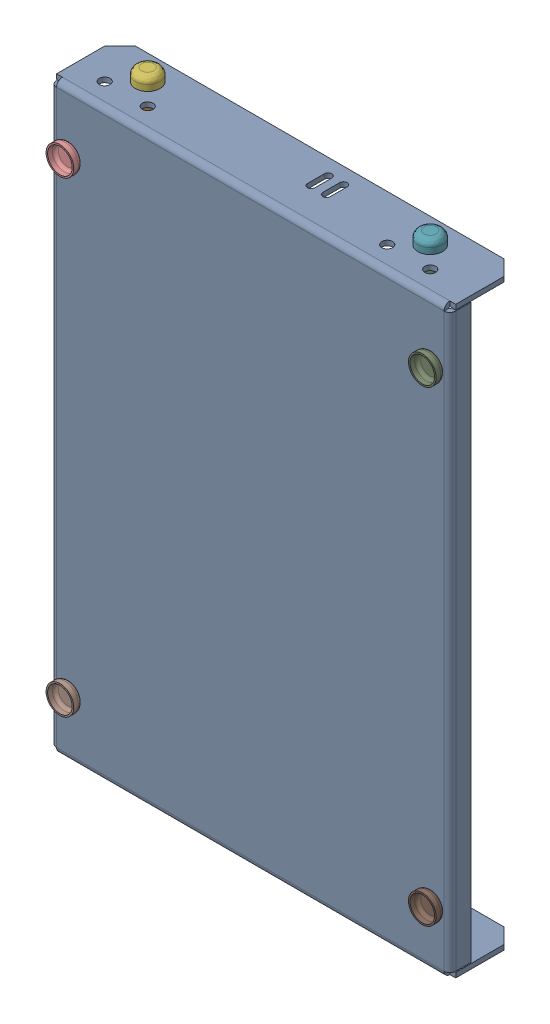
SolidWorks assembly Bed Base_1.step, configuration Default. Lengths in mm.
Overall size (130 198 25.59).
22 component instances, 4 part files, 0 mates.
Components (placement in the parent):
- Bed Frame.step-1: Bed Frame.step [Default] at origin size (130 190 22.59)
  - Bed Frame_1.step-1: Bed Frame_1.step [Default] at (-142 -0.0875 91.0875) size (130 190 22.59)
- Y Axis Shaft.step-1: Y Axis Shaft.step [Default] at (105 0 0) size (8 187 8)
  - Y Axis Shaft_2.step-1: Y Axis Shaft_2.step [Default] at (-295 0 78.0875) size (8 187 8)
- Y Axis Shaft_1.step-1: Y Axis Shaft_1.step [Default] at (140 0 0) size (8 187 8)
  - Y Axis Shaft_2.step-1: Y Axis Shaft_2.step [Default] at (-238 0 78.0875) size (8 187 8)
- Bed Rod Screw Caps.step-1: Bed Rod Screw Caps.step [Default] at (0 -140 0) size (8 4 8)
  - Bed Rod Screw Caps_4.step-1: Bed Rod Screw Caps_4.step [Default] at (-190 44.9125 78.0875) x (1 0 0) z (0 -1 0) size (8 8 4)
- Bed Rod Screw Caps_1.step-1: Bed Rod Screw Caps_1.step [Default] at (0 -130 0) size (8 4 8)
  - Bed Rod Screw Caps_4.step-1: Bed Rod Screw Caps_4.step [Default] at (-98 34.9125 78.0875) x (1 0 0) z (0 -1 0) size (8 8 4)
- Bed Rod Screw Caps_2.step-1: Bed Rod Screw Caps_2.step [Default] at (0 120 0) size (8 4 8)
  - Bed Rod Screw Caps_4.step-1: Bed Rod Screw Caps_4.step [Default] at (-190 -25.0875 78.0875) x (1 0 0) z (0 1 0) size (8 8 4)
- Bed Rod Screw Caps_3.step-1: Bed Rod Screw Caps_3.step [Default] at (0 110 0) size (8 4 8)
  - Bed Rod Screw Caps_4.step-1: Bed Rod Screw Caps_4.step [Default] at (-98 -15.0875 78.0875) x (1 0 0) z (0 1 0) size (8 8 4)
- Bed Spring Cap.step-1: Bed Spring Cap.step [Default] at (-110 0 0) size (9 9 3)
  - Bed Spring Cap_8.step-1: Bed Spring Cap_8.step [Default] at (-91 -76.0875 92.675) size (9 9 3)
- Bed Spring Cap_1.step-1: Bed Spring Cap_1.step [Default] at (-90 0 0) size (9 9 3)
  - Bed Spring Cap_8.step-1: Bed Spring Cap_8.step [Default] at (7 75.9125 92.675) size (9 9 3)
- Bed Spring Cap_2.step-1: Bed Spring Cap_2.step [Default] at (-130 0 0) size (9 9 3)
  - Bed Spring Cap_8.step-1: Bed Spring Cap_8.step [Default] at (-71 75.9125 92.675) size (9 9 3)
- Bed Spring Cap_3.step-1: Bed Spring Cap_3.step [Default] at (-160 0 0) size (9 9 3)
  - Bed Spring Cap_8.step-1: Bed Spring Cap_8.step [Default] at (77 -76.0875 92.675) size (9 9 3)
